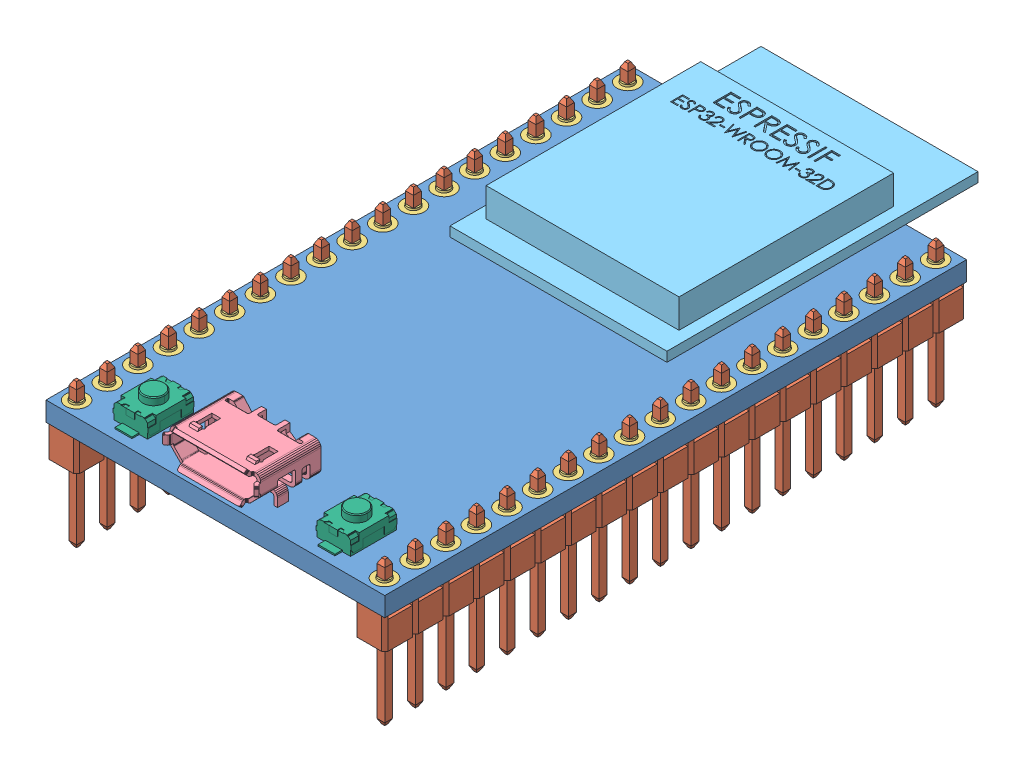
SolidWorks assembly ESP32-WROOM-32D-Assembly.STEP, configuration 默认. Lengths in mm.
Overall size (28.1 14.23 54.86).
8 component instances, 6 part files, 0 mates.
Components (placement in the parent):
- Main-PCB.STEP-1: Main-PCB.STEP [默认] x (1 0 0) z (0 1 0) size (28.1 48.26 1.6)
- zl201-19_p2-54_l48-3_w2-54_h8-9.STEP-1: zl201-19_p2-54_l48-3_w2-54_h8-9.STEP [默认] at (-12.78 -0.25 22.86) x (0 0 1) z (0 -1 0) size (48.26 2.54 11.94)
- zl201-19_p2-54_l48-3_w2-54_h8-9.STEP-2: zl201-19_p2-54_l48-3_w2-54_h8-9.STEP [默认] at (12.78 -0.25 -22.86) x (0 0 -1) z (0 -1 0) size (48.26 2.54 11.94)
- Soldering-Contacts.STEP-1: Soldering-Contacts.STEP [默认] at (0 1.6 0) x (1 0 0) z (0 1 0) size (27.34 47.52 2)
- ab2_usb_micro_smd.wrl.STEP-1: ab2_usb_micro_smd.wrl.STEP [默认] at (0 2.585 24.73) x (1 0 0) z (0 1 0) size (8 5.6 3.57)
- ESP32-chip.STEP-1: ESP32-chip.STEP [默认] at (0 1.6 0) x (1 0 0) z (0 1 0) size (18 25.8 3.2)
- 3x4x2mm_tact_button.STEP-1: 3x4x2mm_tact_button.STEP [默认] at (9.1347 1.6 18.3459) x (0 0 1) z (-1 0 0) size (5 2 2.9)
- 3x4x2mm_tact_button.STEP-2: 3x4x2mm_tact_button.STEP [默认] at (-7.7053 1.6 18.3459) x (0 0 1) z (-1 0 0) size (5 2 2.9)
